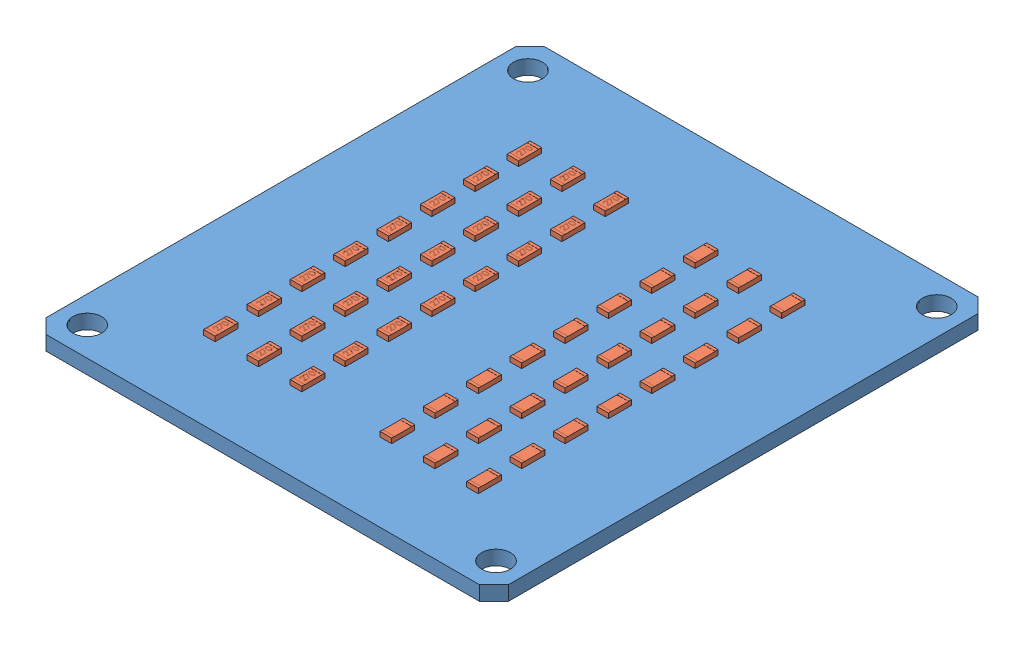
SolidWorks assembly PCBLED, configuration Default. Lengths in mm.
Overall size (64 2.68 69).
49 component instances, 2 part files, 0 mates.
Components (placement in the parent):
- PCBGyrophare-1: PCBGyrophare [Default] at (-2.7185 18.4623 -11.7879) size (64 2 69)
- Resistor1206-1: Resistor1206 [Default] at (-20.1351 20.4413 -30.1056) x (0 0 -1) z (1 0 0) size (3.2 0.7 1.6)
- Resistor1206-2: Resistor1206 [Default] at (-20.1351 20.4413 -24.1056) x (0 0 -1) z (1 0 0) size (3.2 0.7 1.6)
- Resistor1206-3: Resistor1206 [Default] at (-20.1351 20.4413 -18.1056) x (0 0 -1) z (1 0 0) size (3.2 0.7 1.6)
- Resistor1206-4: Resistor1206 [Default] at (-20.1351 20.4413 -12.1056) x (0 0 -1) z (1 0 0) size (3.2 0.7 1.6)
- Resistor1206-5: Resistor1206 [Default] at (-20.1351 20.4413 -6.1056) x (0 0 -1) z (1 0 0) size (3.2 0.7 1.6)
- Resistor1206-6: Resistor1206 [Default] at (-20.1351 20.4413 -0.1056) x (0 0 -1) z (1 0 0) size (3.2 0.7 1.6)
- Resistor1206-7: Resistor1206 [Default] at (-20.1351 20.4413 5.8944) x (0 0 -1) z (1 0 0) size (3.2 0.7 1.6)
- Resistor1206-8: Resistor1206 [Default] at (-20.1351 20.4413 11.8944) x (0 0 -1) z (1 0 0) size (3.2 0.7 1.6)
- Resistor1206-9: Resistor1206 [Default] at (-14.1351 20.4413 -30.1056) x (0 0 -1) z (1 0 0) size (3.2 0.7 1.6)
- Resistor1206-10: Resistor1206 [Default] at (-8.1351 20.4413 -30.1056) x (0 0 -1) z (1 0 0) size (3.2 0.7 1.6)
- Resistor1206-11: Resistor1206 [Default] at (-14.1351 20.4413 -24.1056) x (0 0 -1) z (1 0 0) size (3.2 0.7 1.6)
- Resistor1206-12: Resistor1206 [Default] at (-8.1351 20.4413 -24.1056) x (0 0 -1) z (1 0 0) size (3.2 0.7 1.6)
- Resistor1206-13: Resistor1206 [Default] at (-14.1351 20.4413 -18.1056) x (0 0 -1) z (1 0 0) size (3.2 0.7 1.6)
- Resistor1206-14: Resistor1206 [Default] at (-8.1351 20.4413 -18.1056) x (0 0 -1) z (1 0 0) size (3.2 0.7 1.6)
- Resistor1206-15: Resistor1206 [Default] at (-14.1351 20.4413 -12.1056) x (0 0 -1) z (1 0 0) size (3.2 0.7 1.6)
- Resistor1206-16: Resistor1206 [Default] at (-8.1351 20.4413 -12.1056) x (0 0 -1) z (1 0 0) size (3.2 0.7 1.6)
- Resistor1206-17: Resistor1206 [Default] at (-14.1351 20.4413 -6.1056) x (0 0 -1) z (1 0 0) size (3.2 0.7 1.6)
- Resistor1206-18: Resistor1206 [Default] at (-8.1351 20.4413 -6.1056) x (0 0 -1) z (1 0 0) size (3.2 0.7 1.6)
- Resistor1206-19: Resistor1206 [Default] at (-14.1351 20.4413 -0.1056) x (0 0 -1) z (1 0 0) size (3.2 0.7 1.6)
- Resistor1206-20: Resistor1206 [Default] at (-8.1351 20.4413 -0.1056) x (0 0 -1) z (1 0 0) size (3.2 0.7 1.6)
- Resistor1206-21: Resistor1206 [Default] at (-14.1351 20.4413 5.8944) x (0 0 -1) z (1 0 0) size (3.2 0.7 1.6)
- Resistor1206-22: Resistor1206 [Default] at (-8.1351 20.4413 5.8944) x (0 0 -1) z (1 0 0) size (3.2 0.7 1.6)
- Resistor1206-23: Resistor1206 [Default] at (-14.1351 20.4413 11.8944) x (0 0 -1) z (1 0 0) size (3.2 0.7 1.6)
- Resistor1206-24: Resistor1206 [Default] at (-8.1351 20.4413 11.8944) x (0 0 -1) z (1 0 0) size (3.2 0.7 1.6)
- Resistor1206-25: Resistor1206 [Default] at (14.6982 21.1413 -30.1056) x (0 0 -1) z (-1 0 0) size (3.2 0.7 1.6)
- Resistor1206-26: Resistor1206 [Default] at (14.6982 21.1413 -24.1056) x (0 0 -1) z (-1 0 0) size (3.2 0.7 1.6)
- Resistor1206-27: Resistor1206 [Default] at (14.6982 21.1413 -18.1056) x (0 0 -1) z (-1 0 0) size (3.2 0.7 1.6)
- Resistor1206-28: Resistor1206 [Default] at (14.6982 21.1413 -12.1056) x (0 0 -1) z (-1 0 0) size (3.2 0.7 1.6)
- Resistor1206-29: Resistor1206 [Default] at (14.6982 21.1413 -6.1056) x (0 0 -1) z (-1 0 0) size (3.2 0.7 1.6)
- Resistor1206-30: Resistor1206 [Default] at (14.6982 21.1413 -0.1056) x (0 0 -1) z (-1 0 0) size (3.2 0.7 1.6)
- Resistor1206-31: Resistor1206 [Default] at (14.6982 21.1413 5.8944) x (0 0 -1) z (-1 0 0) size (3.2 0.7 1.6)
- Resistor1206-32: Resistor1206 [Default] at (14.6982 21.1413 11.8944) x (0 0 -1) z (-1 0 0) size (3.2 0.7 1.6)
- Resistor1206-33: Resistor1206 [Default] at (8.6982 21.1413 -30.1056) x (0 0 -1) z (-1 0 0) size (3.2 0.7 1.6)
- Resistor1206-34: Resistor1206 [Default] at (2.6982 21.1413 -30.1056) x (0 0 -1) z (-1 0 0) size (3.2 0.7 1.6)
- Resistor1206-35: Resistor1206 [Default] at (8.6982 21.1413 -24.1056) x (0 0 -1) z (-1 0 0) size (3.2 0.7 1.6)
- Resistor1206-36: Resistor1206 [Default] at (2.6982 21.1413 -24.1056) x (0 0 -1) z (-1 0 0) size (3.2 0.7 1.6)
- Resistor1206-37: Resistor1206 [Default] at (8.6982 21.1413 -18.1056) x (0 0 -1) z (-1 0 0) size (3.2 0.7 1.6)
- Resistor1206-38: Resistor1206 [Default] at (2.6982 21.1413 -18.1056) x (0 0 -1) z (-1 0 0) size (3.2 0.7 1.6)
- Resistor1206-39: Resistor1206 [Default] at (8.6982 21.1413 -12.1056) x (0 0 -1) z (-1 0 0) size (3.2 0.7 1.6)
- Resistor1206-40: Resistor1206 [Default] at (2.6982 21.1413 -12.1056) x (0 0 -1) z (-1 0 0) size (3.2 0.7 1.6)
- Resistor1206-41: Resistor1206 [Default] at (8.6982 21.1413 -6.1056) x (0 0 -1) z (-1 0 0) size (3.2 0.7 1.6)
- Resistor1206-42: Resistor1206 [Default] at (2.6982 21.1413 -6.1056) x (0 0 -1) z (-1 0 0) size (3.2 0.7 1.6)
- Resistor1206-43: Resistor1206 [Default] at (8.6982 21.1413 -0.1056) x (0 0 -1) z (-1 0 0) size (3.2 0.7 1.6)
- Resistor1206-44: Resistor1206 [Default] at (2.6982 21.1413 -0.1056) x (0 0 -1) z (-1 0 0) size (3.2 0.7 1.6)
- Resistor1206-45: Resistor1206 [Default] at (8.6982 21.1413 5.8944) x (0 0 -1) z (-1 0 0) size (3.2 0.7 1.6)
- Resistor1206-46: Resistor1206 [Default] at (2.6982 21.1413 5.8944) x (0 0 -1) z (-1 0 0) size (3.2 0.7 1.6)
- Resistor1206-47: Resistor1206 [Default] at (8.6982 21.1413 11.8944) x (0 0 -1) z (-1 0 0) size (3.2 0.7 1.6)
- Resistor1206-48: Resistor1206 [Default] at (2.6982 21.1413 11.8944) x (0 0 -1) z (-1 0 0) size (3.2 0.7 1.6)
